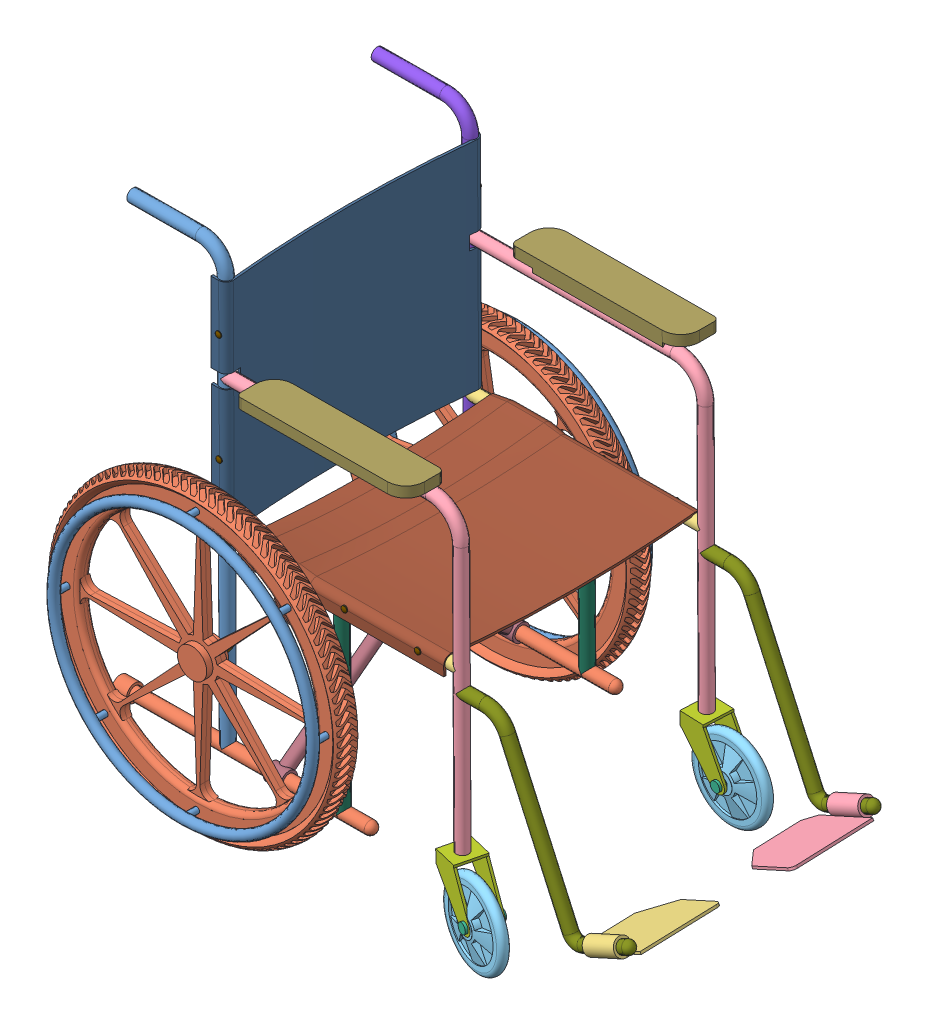
SolidWorks assembly Wheelchair Assembly, configuration Default. Lengths in mm.
Overall size (1268.84 1142.16 701).
45 component instances, 22 part files, 95 mates.
Components (placement in the parent):
- Main Vertical Held-2: Main Vertical Held [Default] at (158.8782 76.583 503.9391) x (0.999987 0.005079 0) z (0 0 1) size (202.5 892.5 25)
- Bottom Cross Support-2: Bottom Cross Support [Default] at (393.8751 77.7766 503.9391) x (0 0 1) z (-0.999987 -0.005079 0) size (35 35 523.5)
- Top Cross Support-1: Top Cross Support [Default] at (636.9648 454.5161 503.9391) x (0 0 1) z (-0.999987 -0.005079 0) size (25 25 480)
- Arm Support_1-1: Arm Support_1 [Default] at (638.364 179.0297 503.9391) x (0.999987 0.005079 0) z (0 0 1) size (492.5 618.29 25)
- Small Wheel-3: Small Wheel [Default] at (690.1434 39.2781 526.624) x (-0.237776 -0.001208 0.971319) z (-0.919519 -0.321926 -0.225496) size (40 165 165)
- Small Wheel Axel_2-2: Small Wheel Axel_2 [Default] at (700.8174 39.3323 483.0203) x (-0.237776 -0.001208 0.971319) z (-0.83837 -0.504735 -0.205858) size (70 20 20)
- Small Wheel Axel_1-5: Small Wheel Axel_1 [Default] at (655.7841 125.8275 539.0232) x (0.237776 0.001208 -0.971319) z (0.971307 0.004933 0.237779) size (60 106.72 95)
- Top Cross Support-2: Top Cross Support [Default] at (636.9648 454.5161 3.9393) x (0 0 1) z (-0.999987 -0.005079 0) size (25 25 480)
- Bottom Cross Support-3: Bottom Cross Support [Default] at (393.8751 77.7766 3.9393) x (0 0 1) z (-0.999987 -0.005079 0) size (35 35 523.5)
- Main Vertical Held 2-1: Main Vertical Held 2 [Default] at (158.8782 76.583 3.9393) x (0.999987 0.005079 0) z (0 0 1) size (202.5 892.5 25)
- Big Wheel Axel-3: Big Wheel Axel [Default] at (157.9512 259.0807 503.9391) x (-0.306826 0.951766 0) z (0 0 1) size (25 25 70)
- Small Wheel Axel_1-6: Small Wheel Axel_1 [Default] at (662.313 125.8606 34.9928) x (0.043266 0.00022 -0.999064) z (0.999051 0.005074 0.043266) size (60 106.72 95)
- Small Wheel-4: Small Wheel [Default] at (694.0211 39.2978 6.3188) x (-0.043266 -0.00022 0.999064) z (-0.668901 0.742793 -0.028804) size (40 165 165)
- Small Wheel Axel_2-3: Small Wheel Axel_2 [Default] at (695.5354 39.3054 -28.6484) x (-0.043266 -0.00022 0.999064) z (-0.997356 0.058449 -0.043179) size (70 20 20)
- Big Wheel Axel-5: Big Wheel Axel [Default] at (157.9512 259.0807 -66.0607) x (-0.506748 0.862094 0) z (0 0 1) size (25 25 70)
- Back Sheet-2: Back Sheet [Default] at (156.9062 464.8343 253.9393) x (0 0 1) z (-0.999987 -0.005079 0) size (529.8 442 30.9)
- Bottom Sheet-2: Bottom Sheet [Default] at (305.2516 452.8313 253.9393) x (0 0 1) z (-0.999987 -0.005079 0) size (539.81 52.09 420.36)
- Arm Rest-1: Arm Rest [Default] at (245.4843 745.0149 563.941) x (0.999987 0.005079 0) z (0.000001 -0.000148 1) size (348 32.5 78)
- Arm Rest-2: Arm Rest [Default] at (588.3685 749.0003 -61.1908) x (-0.999987 -0.005079 0) z (-0.000001 0.000148 -1) size (348 32.5 78)
- Cross Rod-8: Cross Rod [Default] at (241.3771 77.0021 3.9393) x (0.999987 0.005079 0) z (-0.00305 0.600504 0.799616) size (35 35 660.3)
- Cross Rod-9: Cross Rod [Default] at (264.4696 452.6242 3.9393) x (0.999987 0.005079 0) z (0.00305 -0.600504 0.799616) size (35 35 660.3)
- Cross Bolt-2: Cross Bolt [Default] at (288.7907 264.9953 253.9392) x (-0.001672 0.329162 0.944272) z (-0.999987 -0.005079 0) size (10 10 80.18)
- Top-Bottom Cross Support-2: Top-Bottom Cross Support [Default] at (391.968 453.2718 503.9391) x (0.535986 0.002722 -0.844222) z (0.005079 -0.999987 0) size (25 25 377.5)
- Top-Bottom Cross Support-3: Top-Bottom Cross Support [Default] at (391.968 453.2718 3.9393) x (0.673267 0.00342 -0.739392) z (0.005079 -0.999987 0) size (25 25 377.5)
- Arm Support_1-4: Arm Support_1 [Default] at (638.364 179.0297 3.9393) x (0.999987 0.005079 0) z (0 0 1) size (492.5 618.29 25)
- Foot Pad Held-1: Foot Pad Held [Default] at (860.5924 98.4118 504.4536) x (0.910604 0.413279 -0.000664) z (-0.000008 0.001624 0.999999) size (210.62 423.64 25)
- Foot Pad Held-2: Foot Pad Held [Default] at (860.5924 98.4118 4.4536) x (0.910604 0.413279 -0.000664) z (-0.000008 0.001624 0.999999) size (210.62 423.64 25)
- Cross Nut-4: Cross Nut [Default] at (277.923 264.9401 253.9392) x (0.003078 -0.605969 -0.795483) z (0.999987 0.005079 0) size (14 12.12 7.59)
- Cross Nut-5: Cross Nut [Default] at (220.3338 264.6476 253.9392) x (0.003078 -0.605969 -0.795483) z (0.999987 0.005079 0) size (14 12.12 7.59)
- Pin-2: Pin [Default] at (155.145 811.5848 512.5891) x (0.953075 0.302735 0) z (0 0 1) size (12 12 10.2)
- Pin-3: Pin [Default] at (156.2675 590.5876 512.5891) x (0.953075 0.302735 0) z (0 0 1) size (12 12 10.2)
- Pin-4: Pin [Default] at (155.145 811.5848 -4.7107) x (-0.767202 -0.641406 0) z (0 0 -1) size (12 12 10.2)
- Pin-5: Pin [Default] at (156.2675 590.5876 -4.7107) x (-0.767202 -0.641406 0) z (0 0 -1) size (12 12 10.2)
- Big Wheel Hand Held-5: Big Wheel Hand Held [Default] at (157.9512 259.0807 594.4391) x (-1 0 0) z (0 0 -1) size (550 550 40)
- Big Wheel-3: Big Wheel [Default] at (157.9512 259.0807 553.9391) x (1 0 0) z (0 0 1) size (616.56 616.56 48.5)
- Big Wheel-4: Big Wheel [Default] at (157.9512 259.0807 -46.0607) x (-0.794802 0.606869 0) z (0 0 -1) size (616.56 616.56 48.5)
- Big Wheel Hand Held-6: Big Wheel Hand Held [Default] at (157.9512 259.0807 -86.5607) x (0.606869 0.794802 0) z (0 0 1) size (550 550 40)
- Foot Pad2-1: Foot Pad2 [Default] at (861.2249 66.5703 374.2329) x (0.010904 -0.02242 0.999689) z (-0.910604 -0.413279 0.000664) size (197.49 35 140)
- Foot Pad-2: Foot Pad [Default] at (866.3059 55.792 133.815) x (-0.01231 0.025518 -0.999599) z (-0.910604 -0.413279 0.000664) size (197.37 35 140)
- Pin-6: Pin [Default] at (562.4933 454.1379 -4.7107) x (-0.768649 -0.639671 0) z (0 0 -1) size (12 12 10.2)
- Pin-7: Pin [Default] at (412.4953 453.376 -4.7107) x (-0.768649 -0.639671 0) z (0 0 -1) size (12 12 10.2)
- Pin-8: Pin [Default] at (212.4979 452.3602 -6.8107) x (-0.768649 -0.639671 0) z (0 0 -1) size (12 12 10.2)
- Pin-9: Pin [Default] at (212.4979 452.3602 514.6891) x (0.486494 0.873684 0) z (0 0 1) size (12 12 10.2)
- Pin-10: Pin [Default] at (412.4953 453.376 512.5891) x (0.486494 0.873684 0) z (0 0 1) size (12 12 10.2)
- Pin-11: Pin [Default] at (562.4933 454.1379 512.5891) x (-0.034537 0.999403 0) z (0 0 1) size (12 12 10.2)
Mates (geometry in assembly coordinates):
- Parallel2: parallel anti-aligned: cylinder of Main Vertical Held-2 through (104.4093 956.3177 503.9391) axis (-0.999987 -0.005079 0) radius 12.5; cylinder of Bottom Cross Support-2 through (-31.1194 75.618 503.9391) axis (0.999987 0.005079 0) radius 12.5
- Concentric7: concentric anti-aligned: line of Main Vertical Held-2 through (158.8782 76.583 503.9391) axis (-0.005079 0.999987 0); cylinder of Bottom Cross Support-2 through (158.7766 96.5828 503.9391) axis (0.005079 -0.999987 0) radius 12.5
- Coincident21: coincident anti-aligned: plane of Main Vertical Held-2 through (158.8782 76.583 503.9391) normal (0.005079 -0.999987 0); plane of Bottom Cross Support-2 through (158.8782 76.583 503.9391) normal (-0.005079 0.999987 0)
- Concentric8: concentric anti-aligned: cylinder of Main Vertical Held-2 through (177.9707 452.1849 503.9391) axis (-0.999987 -0.005079 0) radius 12.5; cylinder of Top Cross Support-1 through (156.971 452.0782 503.9391) axis (0.999987 0.005079 0) radius 12.5
- Coincident22: coincident anti-aligned: plane of Main Vertical Held-2 through (156.971 452.0782 503.9391) normal (0.999987 0.005079 0); plane of Top Cross Support-1 through (156.971 452.0782 503.9391) normal (-0.999987 -0.005079 0)
- Concentric9: concentric aligned: cylinder of Main Vertical Held-2 through (176.5511 731.6912 503.9391) axis (-0.999987 -0.005079 0) radius 12.5; cylinder of Arm Support_1-1 through (575.5459 733.7178 503.9391) axis (-0.999987 -0.005079 0) radius 12.5
- Coincident23: coincident anti-aligned: plane of Main Vertical Held-2 through (155.5513 731.5846 503.9391) normal (0.999987 0.005079 0); plane of Arm Support_1-1 through (155.5513 731.5846 503.9391) normal (-0.999987 -0.005079 0)
- Parallel3: parallel aligned: cylinder of Main Vertical Held-2 through (158.8782 76.583 503.9391) axis (-0.005079 0.999987 0) radius 12.5; cylinder of Arm Support_1-1 through (638.364 179.0297 503.9391) axis (-0.005079 0.999987 0) radius 12.5
- Concentric26: concentric aligned: cylinder of Small Wheel-3 through (685.3878 39.2539 546.0504) axis (0.237776 0.001208 -0.971319) radius 10; cylinder of Small Wheel Axel_2-2 through (684.1731 39.2477 551.0127) axis (0.237776 0.001208 -0.971319) radius 10
- Concentric28: concentric anti-aligned: cylinder of Small Wheel Axel_2-2 through (684.1731 39.2477 551.0127) axis (0.237776 0.001208 -0.971319) radius 10; cylinder of Small Wheel Axel_1-5 through (686.5508 39.2598 541.2995) axis (-0.237776 -0.001208 0.971319) radius 10
- Width6: width anti-aligned: plane of Small Wheel Axel_2-2 through (684.1731 39.2477 551.0127) normal (-0.237776 -0.001208 0.971319); plane of Small Wheel Axel_2-2 through (700.8174 39.3323 483.0203) normal (0.237776 0.001208 -0.971319); plane of Small Wheel Axel_1-5 through (621.4599 130.6532 468.855) normal (0.237776 0.001208 -0.971319); plane of Small Wheel Axel_1-5 through (685.362 39.2538 546.1561) normal (-0.237776 -0.001208 0.971319)
- Concentric29: concentric aligned: cylinder of Arm Support_1-1 through (638.364 179.0297 503.9391) axis (-0.005079 0.999987 0) radius 12.5; cylinder of Small Wheel Axel_1-5 through (638.622 128.2403 503.9391) axis (-0.005079 0.999987 0) radius 12.5
- Concentric49: concentric aligned: cylinder of Main Vertical Held-2 through (157.9512 259.0807 516.9391) axis (0 0 -1) radius 12.5; cylinder of Big Wheel Axel-3 through (157.9512 259.0807 573.9391) axis (0 0 -1) radius 12.5
- Coincident37: coincident anti-aligned: plane of Main Vertical Held-2 through (157.9512 259.0807 503.9391) normal (0 0 1); plane of Big Wheel Axel-3 through (157.9512 259.0807 503.9391) normal (0 0 -1)
- Concentric50: concentric anti-aligned: cylinder of Bottom Cross Support-3 through (158.7766 96.5828 3.9393) axis (0.005079 -0.999987 0) radius 12.5; cylinder of Main Vertical Held 2-1 through (158.8782 76.583 3.9393) axis (-0.005079 0.999987 0) radius 12.5
- Coincident38: coincident anti-aligned: plane of Bottom Cross Support-3 through (158.8782 76.583 3.9393) normal (-0.005079 0.999987 0); plane of Main Vertical Held 2-1 through (158.8782 76.583 3.9393) normal (0.005079 -0.999987 0)
- Concentric51: concentric anti-aligned: cylinder of Top Cross Support-2 through (156.971 452.0782 3.9393) axis (0.999987 0.005079 0) radius 12.5; cylinder of Main Vertical Held 2-1 through (177.9707 452.1849 3.9393) axis (-0.999987 -0.005079 0) radius 12.5
- Coincident39: coincident anti-aligned: plane of Top Cross Support-2 through (156.971 452.0782 3.9393) normal (-0.999987 -0.005079 0); plane of Main Vertical Held 2-1 through (156.971 452.0782 3.9393) normal (0.999987 0.005079 0)
- Concentric56: concentric aligned: cylinder of Small Wheel Axel_1-6 through (695.1027 39.3032 -18.6578) axis (0.043266 0.00022 -0.999064) radius 10; cylinder of Small Wheel-4 through (693.1558 39.2934 26.3001) axis (0.043266 0.00022 -0.999064) radius 10
- Width8: width anti-aligned: plane of Small Wheel Axel_1-6 through (695.1027 39.3032 -18.6578) normal (-0.043266 -0.00022 0.999064); plane of Small Wheel-4 through (692.9395 39.2923 31.2954) normal (0.043266 0.00022 -0.999064); plane of Small Wheel Axel_1-6 through (694.8864 39.3021 -13.6624) normal (0.043266 0.00022 -0.999064); plane of Small Wheel-4 through (693.1558 39.2934 26.3001) normal (-0.043266 -0.00022 0.999064)
- Concentric57: concentric aligned: cylinder of Small Wheel-4 through (693.1558 39.2934 26.3001) axis (0.043266 0.00022 -0.999064) radius 10; cylinder of Small Wheel Axel_2-3 through (692.5068 39.2901 41.286) axis (0.043266 0.00022 -0.999064) radius 10
- Width9: width anti-aligned: plane of Small Wheel Axel_2-3 through (695.5354 39.3054 -28.6484) normal (0.043266 0.00022 -0.999064); plane of Small Wheel Axel_1-6 through (692.5068 39.2901 41.286) normal (-0.043266 -0.00022 0.999064); plane of Small Wheel Axel_2-3 through (692.7231 39.2912 36.2907) normal (-0.043266 -0.00022 0.999064); plane of Small Wheel Axel_1-6 through (614.931 130.62 -27.1143) normal (0.043266 0.00022 -0.999064)
- Concentric59: concentric anti-aligned: cylinder of Main Vertical Held 2-1 through (157.9512 259.0807 -9.0607) axis (0 0 1) radius 12.5; cylinder of Big Wheel Axel-5 through (157.9512 259.0807 3.9393) axis (0 0 -1) radius 12.5
- Coincident44: coincident anti-aligned: plane of Main Vertical Held 2-1 through (157.9512 259.0807 3.9393) normal (0 0 -1); plane of Big Wheel Axel-5 through (157.9512 259.0807 3.9393) normal (0 0 1)
- Concentric73: concentric aligned: cylinder of Main Vertical Held 2-1 through (158.8782 76.583 3.9393) axis (-0.005079 0.999987 0) radius 12.5; cylinder of Back Sheet-2 through (156.9062 464.8343 3.9393) axis (-0.005079 0.999987 0) radius 10.1
- Concentric74: concentric aligned: cylinder of Main Vertical Held-2 through (158.8782 76.583 503.9391) axis (-0.005079 0.999987 0) radius 12.5; cylinder of Back Sheet-2 through (156.9062 464.8343 503.9393) axis (-0.005079 0.999987 0) radius 10.1
- Concentric75: concentric aligned: cylinder of Top Cross Support-1 through (156.971 452.0782 503.9391) axis (0.999987 0.005079 0) radius 12.5; cylinder of Bottom Sheet-2 through (340.2512 453.0091 503.9393) axis (0.999987 0.005079 0) radius 10.1
- Concentric76: concentric aligned: cylinder of Top Cross Support-2 through (156.971 452.0782 3.9393) axis (0.999987 0.005079 0) radius 12.5; cylinder of Bottom Sheet-2 through (340.2512 453.0091 3.9393) axis (0.999987 0.005079 0) radius 10.1
- Concentric77: concentric aligned: cylinder of Arm Support_1-1 through (575.5459 733.7178 503.9391) axis (-0.999987 -0.005079 0) radius 12.5; cylinder of Arm Rest-1 through (539.5464 733.5349 503.9391) axis (-0.999987 -0.005079 0) radius 12.5
- Concentric90: concentric anti-aligned: cylinder of Top Cross Support-1 through (156.971 452.0782 503.9391) axis (0.999987 0.005079 0) radius 12.5; cylinder of Cross Rod-8 through (256.9697 452.5861 503.9391) axis (-0.999987 -0.005079 0) radius 12.5
- Concentric91: concentric anti-aligned: cylinder of Bottom Cross Support-3 through (-31.1194 75.618 3.9393) axis (0.999987 0.005079 0) radius 12.5; cylinder of Cross Rod-8 through (258.8769 77.0909 3.9393) axis (-0.999987 -0.005079 0) radius 12.5
- Concentric92: concentric anti-aligned: cylinder of Top Cross Support-2 through (156.971 452.0782 3.9393) axis (0.999987 0.005079 0) radius 12.5; cylinder of Cross Rod-9 through (281.9694 452.7131 3.9393) axis (-0.999987 -0.005079 0) radius 12.5
- Concentric93: concentric anti-aligned: cylinder of Bottom Cross Support-2 through (-31.1194 75.618 503.9391) axis (0.999987 0.005079 0) radius 12.5; cylinder of Cross Rod-9 through (283.8766 77.2179 503.9391) axis (-0.999987 -0.005079 0) radius 12.5
- Concentric96: concentric aligned: cylinder of Cross Rod-9 through (-47.2228 263.2886 253.9392) axis (0.999987 0.005079 0) radius 5; cylinder of Cross Bolt-2 through (218.6116 264.6388 253.9392) axis (0.999987 0.005079 0) radius 5
- Concentric97: concentric aligned: cylinder of Cross Rod-8 through (-72.2224 263.1617 253.9392) axis (0.999987 0.005079 0) radius 5; cylinder of Cross Bolt-2 through (218.6116 264.6388 253.9392) axis (0.999987 0.005079 0) radius 5
- Concentric109: concentric anti-aligned: cylinder of Bottom Cross Support-2 through (392.7958 290.2739 503.9391) axis (0.005079 -0.999987 0) radius 12.5; cylinder of Top Cross Support-1 through (392.0695 433.272 503.9391) axis (-0.005079 0.999987 0) radius 12.5
- Concentric111: concentric anti-aligned: cylinder of Bottom Cross Support-2 through (392.7958 290.2739 503.9391) axis (0.005079 -0.999987 0) radius 12.5; cylinder of Top-Bottom Cross Support-2 through (393.8218 88.2765 503.9391) axis (-0.005079 0.999987 0) radius 12.5
- Concentric112: concentric aligned: cylinder of Top Cross Support-1 through (392.0695 433.272 503.9391) axis (-0.005079 0.999987 0) radius 12.5; cylinder of Top-Bottom Cross Support-2 through (393.8218 88.2765 503.9391) axis (-0.005079 0.999987 0) radius 12.5
- Coincident55: coincident anti-aligned: plane of Top Cross Support-1 through (391.968 453.2718 503.9391) normal (0.005079 -0.999987 0); plane of Top-Bottom Cross Support-2 through (391.968 453.2718 503.9391) normal (-0.005079 0.999987 0)
- Concentric113: concentric anti-aligned: cylinder of Top Cross Support-2 through (392.0695 433.272 3.9393) axis (-0.005079 0.999987 0) radius 12.5; cylinder of Bottom Cross Support-3 through (392.7958 290.2739 3.9393) axis (0.005079 -0.999987 0) radius 12.5
- Concentric114: concentric anti-aligned: cylinder of Bottom Cross Support-3 through (392.7958 290.2739 3.9393) axis (0.005079 -0.999987 0) radius 12.5; cylinder of Top-Bottom Cross Support-3 through (393.8218 88.2765 3.9393) axis (-0.005079 0.999987 0) radius 12.5
- Concentric115: concentric aligned: cylinder of Top Cross Support-2 through (392.0695 433.272 3.9393) axis (-0.005079 0.999987 0) radius 12.5; cylinder of Top-Bottom Cross Support-3 through (393.8218 88.2765 3.9393) axis (-0.005079 0.999987 0) radius 12.5
- Coincident56: coincident anti-aligned: plane of Top Cross Support-2 through (391.968 453.2718 3.9393) normal (0.005079 -0.999987 0); plane of Top-Bottom Cross Support-3 through (391.968 453.2718 3.9393) normal (-0.005079 0.999987 0)
- Coincident60: coincident anti-aligned: plane of Arm Support_1-1 through (638.622 128.2403 503.9391) normal (0.005079 -0.999987 0); plane of Small Wheel Axel_1-5 through (638.622 128.2403 503.9391) normal (-0.005079 0.999987 0)
- Concentric116: concentric aligned: cylinder of Main Vertical Held 2-1 through (176.5511 731.6912 3.9393) axis (-0.999987 -0.005079 0) radius 12.5; cylinder of Arm Support_1-4 through (575.5459 733.7178 3.9393) axis (-0.999987 -0.005079 0) radius 12.5
- Coincident62: coincident anti-aligned: plane of Main Vertical Held 2-1 through (155.5513 731.5846 3.9393) normal (0.999987 0.005079 0); plane of Arm Support_1-4 through (155.5513 731.5846 3.9393) normal (-0.999987 -0.005079 0)
- Parallel20: parallel aligned: cylinder of Arm Support_1-1 through (638.364 179.0297 503.9391) axis (-0.005079 0.999987 0) radius 12.5; cylinder of Arm Support_1-4 through (638.364 179.0297 3.9393) axis (-0.005079 0.999987 0) radius 12.5
- Concentric118: concentric aligned: cylinder of Small Wheel Axel_1-6 through (638.622 128.2403 3.9393) axis (-0.005079 0.999987 0) radius 12.5; cylinder of Arm Support_1-4 through (638.364 179.0297 3.9393) axis (-0.005079 0.999987 0) radius 12.5
- Coincident63: coincident anti-aligned: plane of Small Wheel Axel_1-6 through (638.622 128.2403 3.9393) normal (-0.005079 0.999987 0); plane of Arm Support_1-4 through (638.622 128.2403 3.9393) normal (0.005079 -0.999987 0)
- Concentric119: concentric aligned: cylinder of Arm Support_1-1 through (687.9598 414.2846 503.9391) axis (-0.999987 -0.005079 0) radius 12.5; cylinder of Foot Pad Held-1 through (684.7698 414.2684 503.9391) axis (-0.999987 -0.005079 0) radius 12.5
- Coincident64: coincident anti-aligned: plane of Arm Support_1-1 through (637.1705 414.0267 503.9391) normal (0.999987 0.005079 0); plane of Foot Pad Held-1 through (637.1705 414.0267 503.9391) normal (-0.999987 -0.005079 0)
- Concentric120: concentric aligned: cylinder of Arm Support_1-4 through (687.9598 414.2846 3.9393) axis (-0.999987 -0.005079 0) radius 12.5; cylinder of Foot Pad Held-2 through (684.7698 414.2684 3.9391) axis (-0.999987 -0.005079 0) radius 12.5
- Coincident65: coincident anti-aligned: plane of Arm Support_1-4 through (637.1705 414.0267 3.9393) normal (0.999987 0.005079 0); plane of Foot Pad Held-2 through (637.1705 414.0267 3.9391) normal (-0.999987 -0.005079 0)
- Distance1: distance = 65 mm: plane of Cross Rod-8 through (221.9702 452.4083 503.9391) normal (-0.999987 -0.005079 0); cylinder of Main Vertical Held-2 through (158.8782 76.583 503.9391) axis (-0.005079 0.999987 0) radius 12.5
- Distance3: distance = 90 mm: plane of Cross Rod-9 through (246.9698 452.5353 3.9393) normal (-0.999987 -0.005079 0); cylinder of Main Vertical Held 2-1 through (158.8782 76.583 3.9393) axis (-0.005079 0.999987 0) radius 12.5
- Concentric125: concentric anti-aligned: cylinder of Cross Bolt-2 through (218.6116 264.6388 253.9392) axis (0.999987 0.005079 0) radius 5; cylinder of Cross Nut-4 through (285.5129 264.9786 253.9392) axis (-0.999987 -0.005079 0) radius 5
- Tangent18: tangent anti-aligned: plane of Cross Nut-4 through (277.923 264.9401 253.9392) normal (-0.999987 -0.005079 0); cylinder of Cross Rod-9 through (266.3768 77.129 503.9391) axis (-0.00305 0.600504 -0.799616) radius 12.5
- Concentric126: concentric anti-aligned: cylinder of Cross Bolt-2 through (218.6116 264.6388 253.9392) axis (0.999987 0.005079 0) radius 5; cylinder of Cross Nut-5 through (227.9237 264.6861 253.9392) axis (-0.999987 -0.005079 0) radius 5
- Tangent19: tangent anti-aligned: cylinder of Cross Rod-8 through (239.4699 452.4972 503.9391) axis (0.00305 -0.600504 -0.799616) radius 12.5; plane of Cross Nut-5 through (227.9237 264.6861 253.9392) normal (0.999987 0.005079 0)
- Distance7: distance = 80 mm: plane of Arm Rest-2 through (250.2637 768.7777 -23.1876) normal (-0.999987 -0.005079 0); cylinder of Back Sheet-2 through (156.9062 464.8343 3.9393) axis (-0.005079 0.999987 0) radius 14.9
- Distance8: distance = 80 mm: cylinder of Back Sheet-2 through (156.9062 464.8343 503.9393) axis (-0.005079 0.999987 0) radius 14.9; plane of Arm Rest-1 through (235.3752 766.4698 523.9442) normal (-0.999987 -0.005079 0)
- Concentric129: concentric aligned: cylinder of Back Sheet-2 through (155.145 811.5848 523.9393) axis (0 0 -1) radius 5; cylinder of Pin-2 through (155.145 811.5848 518.8391) axis (0 0 -1) radius 3
- Tangent25: tangent anti-aligned: cylinder of Back Sheet-2 through (156.9062 464.8343 503.9393) axis (-0.005079 0.999987 0) radius 14.9; plane of Pin-2 through (155.145 811.5848 518.8391) normal (0 0 -1)
- Concentric131: concentric aligned: cylinder of Back Sheet-2 through (156.2675 590.5876 523.9393) axis (0 0 -1) radius 5; cylinder of Pin-3 through (156.2675 590.5876 518.8391) axis (0 0 -1) radius 3
- Tangent26: tangent anti-aligned: cylinder of Back Sheet-2 through (156.9062 464.8343 503.9393) axis (-0.005079 0.999987 0) radius 14.9; plane of Pin-3 through (156.2675 590.5876 518.8391) normal (0 0 -1)
- Concentric133: concentric aligned: cylinder of Back Sheet-2 through (155.145 811.5848 -16.0607) axis (0 0 1) radius 5; cylinder of Pin-4 through (155.145 811.5848 -10.9607) axis (0 0 1) radius 3
- Tangent27: tangent anti-aligned: cylinder of Back Sheet-2 through (156.9062 464.8343 3.9393) axis (-0.005079 0.999987 0) radius 14.9; plane of Pin-4 through (155.145 811.5848 -10.9607) normal (0 0 1)
- Concentric135: concentric aligned: cylinder of Back Sheet-2 through (156.2675 590.5876 -16.0607) axis (0 0 1) radius 5; cylinder of Pin-5 through (156.2675 590.5876 -10.9607) axis (0 0 1) radius 3
- Tangent28: tangent anti-aligned: cylinder of Back Sheet-2 through (156.9062 464.8343 3.9393) axis (-0.005079 0.999987 0) radius 14.9; plane of Pin-5 through (156.2675 590.5876 -10.9607) normal (0 0 1)
- Concentric148: concentric aligned: cylinder of Big Wheel Hand Held-5 through (345.3345 446.464 564.4391) axis (0 0 1) radius 6; cylinder of Big Wheel-3 through (345.3345 446.464 564.4391) axis (0 0 1) radius 6
- Concentric149: concentric aligned: cylinder of Big Wheel Hand Held-5 through (422.9512 259.0807 564.4391) axis (0 0 1) radius 6; cylinder of Big Wheel-3 through (422.9512 259.0807 564.4391) axis (0 0 1) radius 6
- Coincident69: coincident anti-aligned: plane of Big Wheel Hand Held-5 through (345.3345 446.464 564.4391) normal (0 0 -1); plane of Big Wheel-3 through (345.3345 446.464 564.4391) normal (0 0 1)
- Concentric150: concentric aligned: cylinder of Big Wheel Axel-3 through (157.9512 259.0807 573.9391) axis (0 0 -1) radius 12.5; cylinder of Big Wheel-3 through (157.9512 259.0807 573.9391) axis (0 0 -1) radius 12.5
- Coincident70: coincident anti-aligned: plane of Big Wheel Axel-3 through (157.9512 259.0807 573.9391) normal (0 0 1); plane of Big Wheel-3 through (157.9512 259.0807 573.9391) normal (0 0 -1)
- Concentric151: concentric anti-aligned: cylinder of Big Wheel Axel-5 through (157.9512 259.0807 3.9393) axis (0 0 -1) radius 12.5; cylinder of Big Wheel-4 through (157.9512 259.0807 -66.0607) axis (0 0 1) radius 12.5
- Coincident71: coincident anti-aligned: plane of Big Wheel Axel-5 through (157.9512 259.0807 -66.0607) normal (0 0 -1); plane of Big Wheel-4 through (157.9512 259.0807 -66.0607) normal (0 0 1)
- Concentric152: concentric aligned: cylinder of Big Wheel-4 through (318.7714 469.7033 -56.5607) axis (0 0 -1) radius 6; cylinder of Big Wheel Hand Held-6 through (318.7714 469.7033 -56.5607) axis (0 0 -1) radius 6
- Concentric153: concentric aligned: cylinder of Big Wheel-4 through (122.7356 521.7304 -56.5607) axis (0 0 -1) radius 6; cylinder of Big Wheel Hand Held-6 through (122.7356 521.7304 -56.5607) axis (0 0 -1) radius 6
- Coincident72: coincident anti-aligned: plane of Big Wheel-4 through (318.7714 469.7033 -56.5607) normal (0 0 -1); plane of Big Wheel Hand Held-6 through (318.7714 469.7033 -56.5607) normal (0 0 1)
- Concentric156: concentric anti-aligned: cylinder of Foot Pad Held-1 through (978.1305 129.7932 504.4036) axis (-0.910604 -0.413279 0.000664) radius 12.5; cylinder of Foot Pad2-1 through (903.0056 95.6977 504.4583) axis (0.910604 0.413279 -0.000664) radius 12.5
- Distance10: distance = 0 mm anti-aligned: plane of Foot Pad2-1 through (973.8444 108.9709 491.7425) normal (0.910604 0.413279 -0.000664); sphere of Foot Pad Held-1
- Concentric157: concentric anti-aligned: cylinder of Foot Pad Held-2 through (978.1305 129.7932 4.4036) axis (-0.910604 -0.413279 0.000664) radius 12.5; cylinder of Foot Pad-2 through (857.933 75.2415 4.4912) axis (0.910604 0.413279 -0.000664) radius 12.5
- Distance11: distance = 0 mm anti-aligned: plane of Foot Pad-2 through (972.0606 112.9403 16.1738) normal (0.910604 0.413279 -0.000664); sphere of Foot Pad Held-2
- Concentric158: concentric aligned: cylinder of Bottom Sheet-2 through (562.4933 454.1379 -29.0607) axis (0 0 1) radius 6; cylinder of Pin-6 through (562.4933 454.1379 -10.9607) axis (0 0 1) radius 3
- Tangent33: tangent anti-aligned: cylinder of Bottom Sheet-2 through (340.2512 453.0091 3.9393) axis (0.999987 0.005079 0) radius 14.9; plane of Pin-6 through (562.4933 454.1379 -10.9607) normal (0 0 1)
- Concentric159: concentric aligned: cylinder of Bottom Sheet-2 through (412.4953 453.376 -29.0607) axis (0 0 1) radius 6; cylinder of Pin-7 through (412.4953 453.376 -10.9607) axis (0 0 1) radius 3
- Tangent34: tangent anti-aligned: cylinder of Bottom Sheet-2 through (340.2512 453.0091 3.9393) axis (0.999987 0.005079 0) radius 14.9; plane of Pin-7 through (412.4953 453.376 -10.9607) normal (0 0 1)
- Concentric160: concentric aligned: cylinder of Bottom Sheet-2 through (212.4979 452.3602 -29.0607) axis (0 0 1) radius 6; cylinder of Pin-8 through (212.4979 452.3602 -13.0607) axis (0 0 1) radius 3
- Distance12: distance = 17 mm: cylinder of Top Cross Support-2 through (156.971 452.0782 3.9393) axis (0.999987 0.005079 0) radius 12.5; plane of Pin-8 through (212.4979 452.3602 -13.0607) normal (0 0 1)
- Concentric161: concentric aligned: cylinder of Bottom Sheet-2 through (212.4979 452.3602 536.9393) axis (0 0 -1) radius 6; cylinder of Pin-9 through (212.4979 452.3602 520.9391) axis (0 0 -1) radius 3
- Distance13: distance = 17 mm: cylinder of Top Cross Support-1 through (156.971 452.0782 503.9391) axis (0.999987 0.005079 0) radius 12.5; plane of Pin-9 through (212.4979 452.3602 520.9391) normal (0 0 -1)
- Concentric162: concentric aligned: cylinder of Bottom Sheet-2 through (412.4953 453.376 536.9393) axis (0 0 -1) radius 6; cylinder of Pin-10 through (412.4953 453.376 518.8391) axis (0 0 -1) radius 3
- Tangent39: tangent anti-aligned: cylinder of Bottom Sheet-2 through (340.2512 453.0091 503.9393) axis (0.999987 0.005079 0) radius 14.9; plane of Pin-10 through (412.4953 453.376 518.8391) normal (0 0 -1)
- Concentric164: concentric aligned: cylinder of Bottom Sheet-2 through (562.4933 454.1379 536.9393) axis (0 0 -1) radius 6; cylinder of Pin-11 through (562.4933 454.1379 535.9061) axis (0 0 -1) radius 3
- Tangent47: tangent anti-aligned: cylinder of Bottom Sheet-2 through (340.2512 453.0091 503.9393) axis (0.999987 0.005079 0) radius 14.9; plane of Pin-11 through (562.4933 454.1379 518.8391) normal (0 0 -1)
